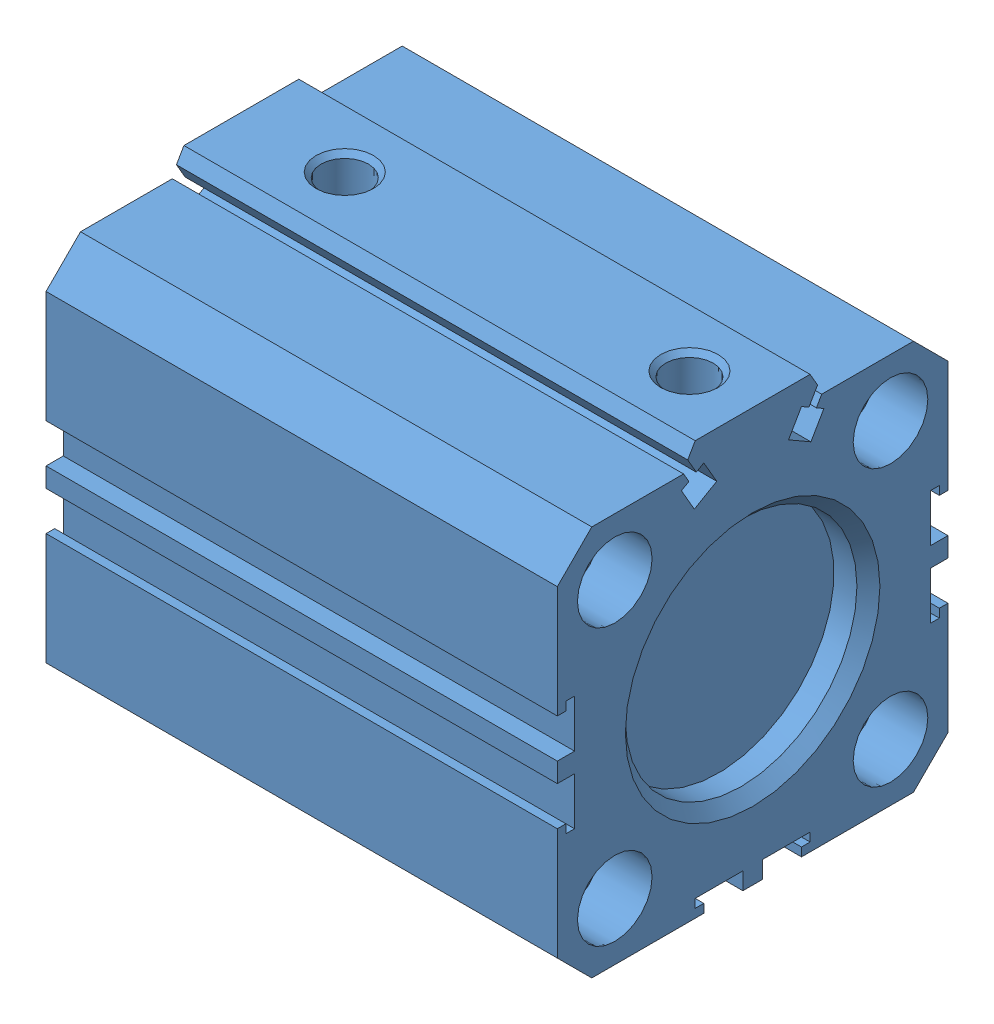
SolidWorks assembly cylinder_sda-20x25, configuration Default. Lengths in mm.
Overall size (50 36 34).
2 component instances, 2 part files, 4 mates.
Components (placement in the parent):
- cylinder_sda-20x25_01-1: cylinder_sda-20x25_01 [Default] at origin size (46 36 34)
- cylinder_sda-20x25_02-1: cylinder_sda-20x25_02 [Default] x (1 0 0) z (0 -0.480504 0.876992) size (29 8 8)
Mates (geometry in assembly coordinates):
- Concentric2: concentric aligned: circle of cylinder_sda-20x25_01-1; cylinder of cylinder_sda-20x25_02-1 through (-5.5 0 0) axis (1 0 0) radius 4
- LimitDistance1: limit distance = 4 mm aligned: plane of cylinder_sda-20x25_02-1 through (-5.5 0 0) normal (-1 0 0); plane of cylinder_sda-20x25_01-1 through (-1.5 0 0) normal (-1 0 0)
- Distance1: distance = 25 mm aligned: plane of cylinder_sda-20x25_02-1 through (-26.5 0 0) normal (-1 0 0); plane of cylinder_sda-20x25_01-1 through (-1.5 0 0) normal (-1 0 0)
- Distance2: distance = 4 mm aligned: plane of cylinder_sda-20x25_02-1 through (-5.5 0 0) normal (-1 0 0); plane of cylinder_sda-20x25_01-1 through (-1.5 0 0) normal (-1 0 0)
